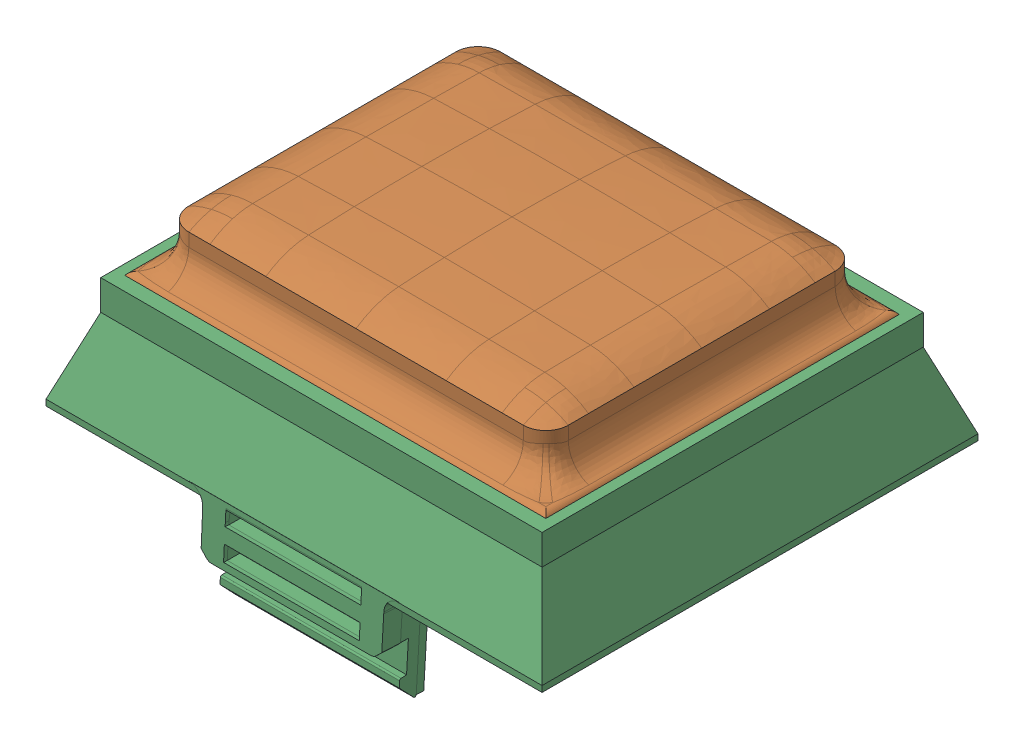
SolidWorks assembly ContiALL, configuration 默认. Lengths in mm.
Overall size (33 18.3 29.5).
5 component instances, 5 part files, 13 mates.
Components (placement in the parent):
- Conti_lensall-1: Conti_lensall [默认] at origin size (28.33 2.18 23.83)
- Conti_Topskin-1: Conti_Topskin [默认] at (0.0001 2 0.2499) size (28.02 6.25 23.52)
- Conti_SupportBase-2: Conti_SupportBase [默认] at origin size (33 14.05 29.5)
- InsideSkin_conti-1: InsideSkin_conti [默认] at (0.0001 0 0.2499) size (23.8 5.48 19.29)
- continuous-1: continuous [默认] at (-10.2499 23.7 -8.2501) x (1 0 0) z (0 -1 0) size (22 16 0.4)
Mates (geometry in assembly coordinates):
- 重合6: coordinate: point of SupportBase-2
- 重合7: coincident anti-aligned: plane of lensall-1 through (13.75 19 -11.5) normal (0.939693 0.34202 0); plane of SupportBase-2 through (13.75 19 12.7803) normal (-0.939693 -0.34202 0)
- 同心5: concentric aligned: cylinder of lensall-1 through (13.3294 18.6938 -11.0794) axis (-0.323616 0.889126 0.323616) radius 0.5; cylinder of SupportBase-2 through (10.7866 25.6801 -8.5366) axis (-0.323616 0.889126 0.323616) radius 0.5
- 重合8: coincident anti-aligned: plane of lensall-1 through (0 18 0) normal (0 -1 0); plane of SupportBase-2 through (0 18 0) normal (0 1 0)
- 重合9: coincident anti-aligned: plane of lensall-1 through (0 19 0) normal (0 1 0); plane of Board3Con1612611OriginalSkin_TOP-1 through (0.0001 19 0.2499) normal (0 -1 0)
- 重合10: coincident anti-aligned: plane of Board3Con1612611OriginalSkin_TOP-1 through (0.0001 19 11.7499) normal (0 0 1); plane of SupportBase-2 through (-13.5999 21 11.7499) normal (0 0 -1)
- 重合11: coincident anti-aligned: plane of Board3Con1612611OriginalSkin_TOP-1 through (14.0001 19 0.2499) normal (1 0 0); plane of SupportBase-2 through (14.0001 21 11.7499) normal (-1 0 0)
- 重合12: coincident anti-aligned: plane of Conti_lensall-1 through (0 19 0) normal (0 1 0); plane of InsideSkin_conti-1 through (16.1514 19 15.8656) normal (0 -1 0)
- 同心6: concentric anti-aligned: cylinder of Conti_Board3Con1612611OriginalSkin_TOP-1 through (-11.3749 24 8.6249) axis (0 -1 0) radius 0.7; cylinder of InsideSkin_conti-1 through (-11.3749 17.7531 8.6249) axis (0 1 0) radius 0.7
- 宽度1: width anti-aligned: plane of InsideSkin_conti-1; plane of InsideSkin_conti-1; plane of continuous-1; plane of continuous-1
- 宽度2: width aligned: plane of continuous-1; plane of continuous-1; plane of InsideSkin_conti-1; plane of InsideSkin_conti-1
- 重合13: coincident anti-aligned: plane of InsideSkin_conti-1 through (-10.0011 23.7 9.0044) normal (0 -1 0); plane of continuous-1 through (2.8305 23.7 -0.5534) normal (0 1 0)
- 同心7: concentric anti-aligned: cylinder of Conti_Board3Con1612611OriginalSkin_TOP-1 through (-11.3749 24 -9.1251) axis (0 -1 0) radius 0.7; cylinder of InsideSkin_conti-1 through (2.8602 17.7531 -1.9783) axis (0 1 0) radius 0.7
